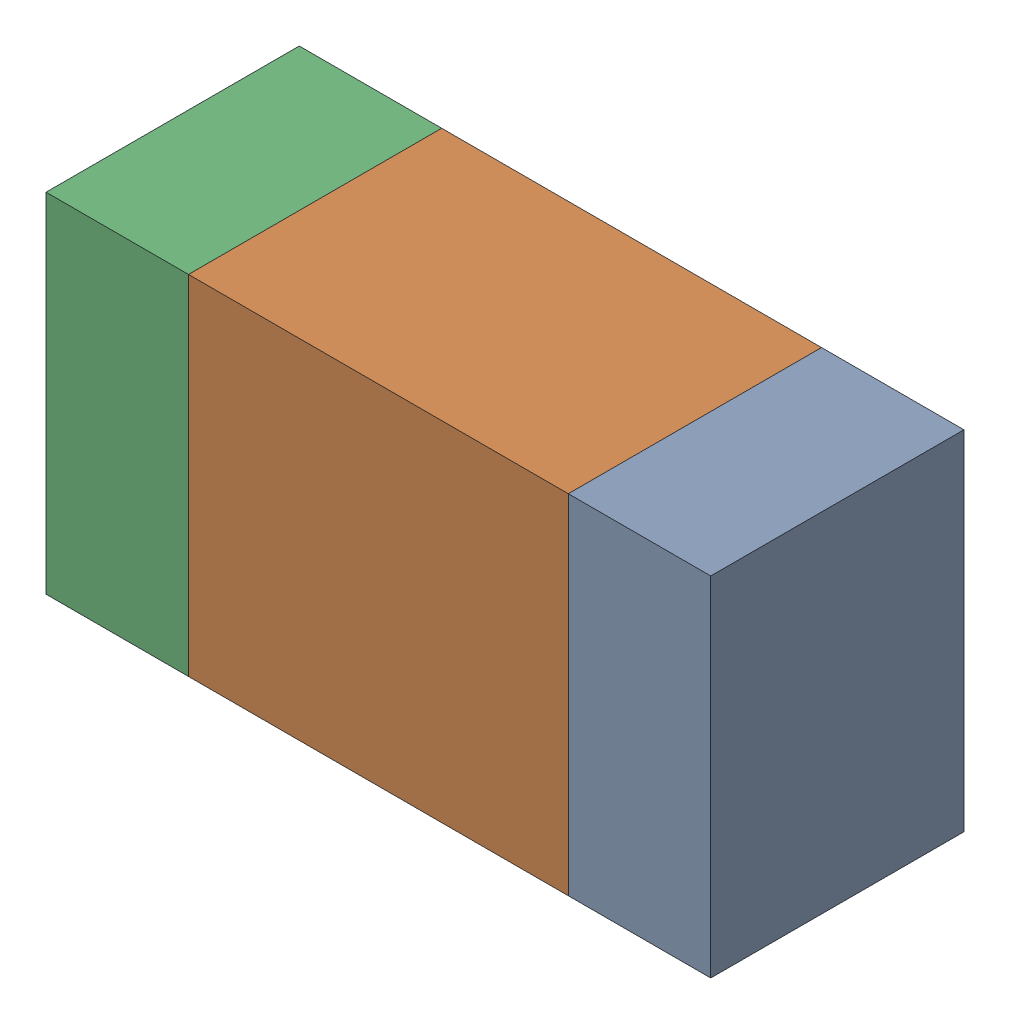
SolidWorks assembly R206PCB, configuration Default. Lengths in mm.
Overall size (1.05 0.55 0.4).
6 component instances, 2 part files, 0 mates.
Components (placement in the parent):
- 854785432-1: 854785432 [Default] at (83.5124 78.3999 0) size (0.22 0.55 0.4)
  - Extruded-1: Extruded [Default] at origin size (0.22 0.55 0.4)
- 854785568-1: 854785568 [Default] at (83.0999 78.3999 0) size (0.6 0.55 0.4)
  - Extruded_2-1: Extruded_2 [Default] at origin size (0.6 0.55 0.4)
- 854785432-2: 854785432 [Default] at (82.6874 78.3999 0) size (0.22 0.55 0.4)
  - Extruded-1: Extruded [Default] at origin size (0.22 0.55 0.4)
